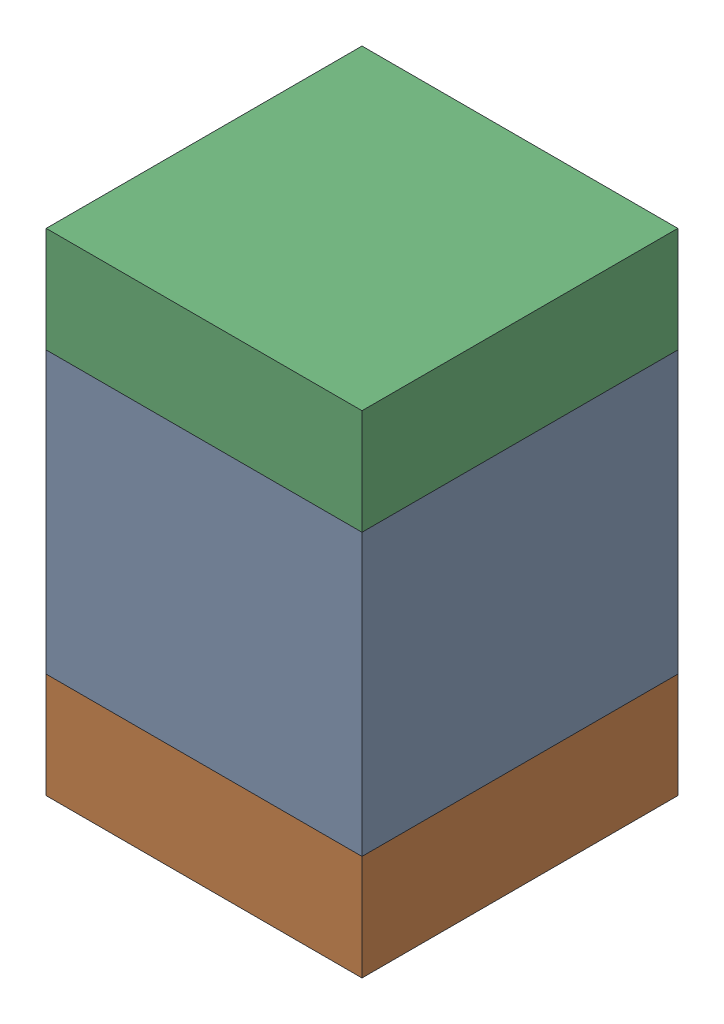
SolidWorks assembly C3.step, configuration Default. Lengths in mm.
Overall size (1.35 2.1 1.35).
6 component instances, 2 part files, 0 mates.
Components (placement in the parent):
- 5958432416.step-1: 5958432416.step [Default] at (50.292 48.641 0) size (1.35 1.2 1.35)
  - Extruded-7.step-1: Extruded-7.step [Default] at origin size (1.35 1.2 1.35)
- 5958432016.step-1: 5958432016.step [Default] at (50.292 47.816 0) size (1.35 0.45 1.35)
  - Extruded-8.step-1: Extruded-8.step [Default] at origin size (1.35 0.45 1.35)
- 5958432016.step-2: 5958432016.step [Default] at (50.292 49.466 0) size (1.35 0.45 1.35)
  - Extruded-8.step-1: Extruded-8.step [Default] at origin size (1.35 0.45 1.35)
